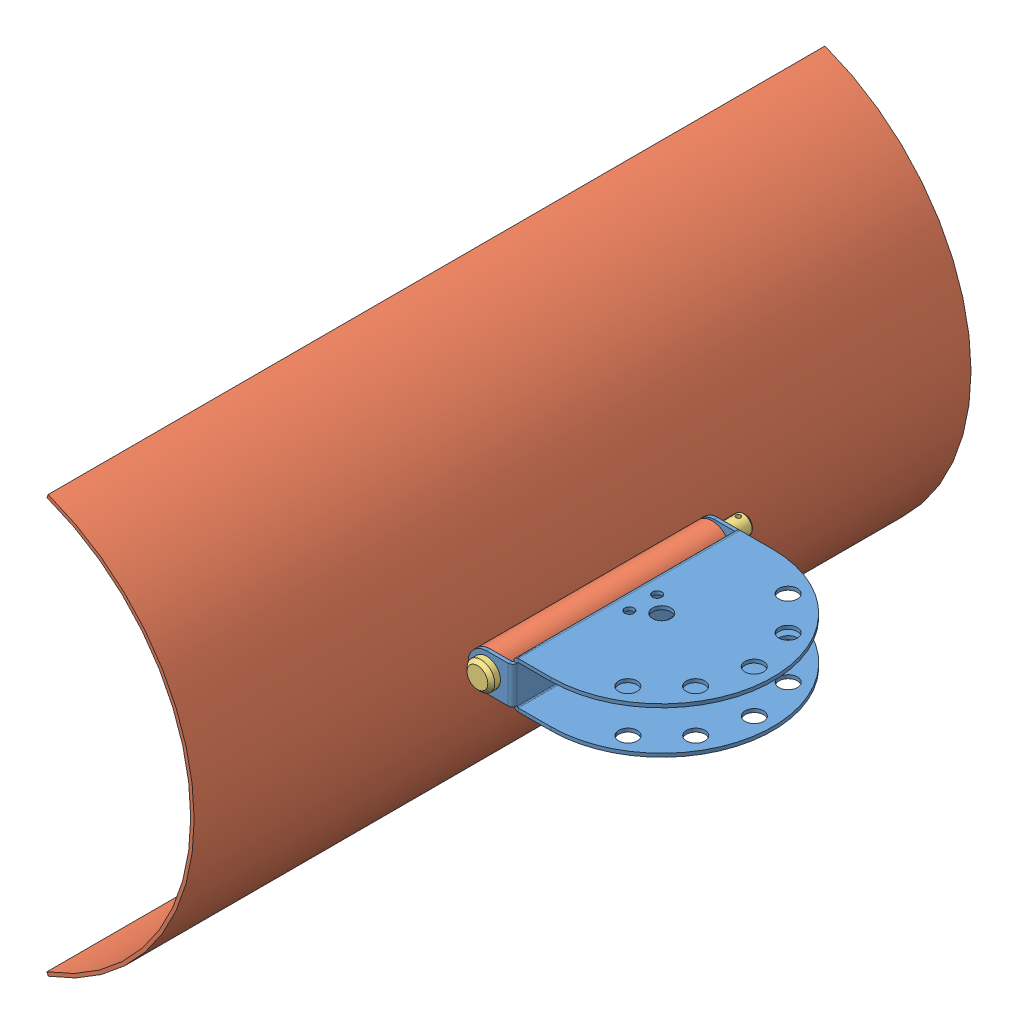
SolidWorks assembly Assem1, configuration Default. Lengths in mm.
Overall size (230.97 286.42 533.4).
3 component instances, 3 part files, 2 mates.
Components (placement in the parent):
- pin and hole sheet metal-1: pin and hole sheet metal [Default] at (66.8764 89.9544 116.0222) size (129.88 31.73 158.64)
- plow blade-1: plow blade [Default] at (25.9871 76.5178 40.5588) size (126.49 286.42 533.4)
- blade pivot pin-2: blade pivot pin [Default] at (25.9871 76.5178 17.5401) size (19.05 19.05 184.15)
Mates (geometry in assembly coordinates):
- Coincident1: coincident aligned: circle of pin and hole sheet metal-1; circle of plow blade-1
- Coincident2: coincident aligned: circle of pin and hole sheet metal-1; circle of blade pivot pin-2
